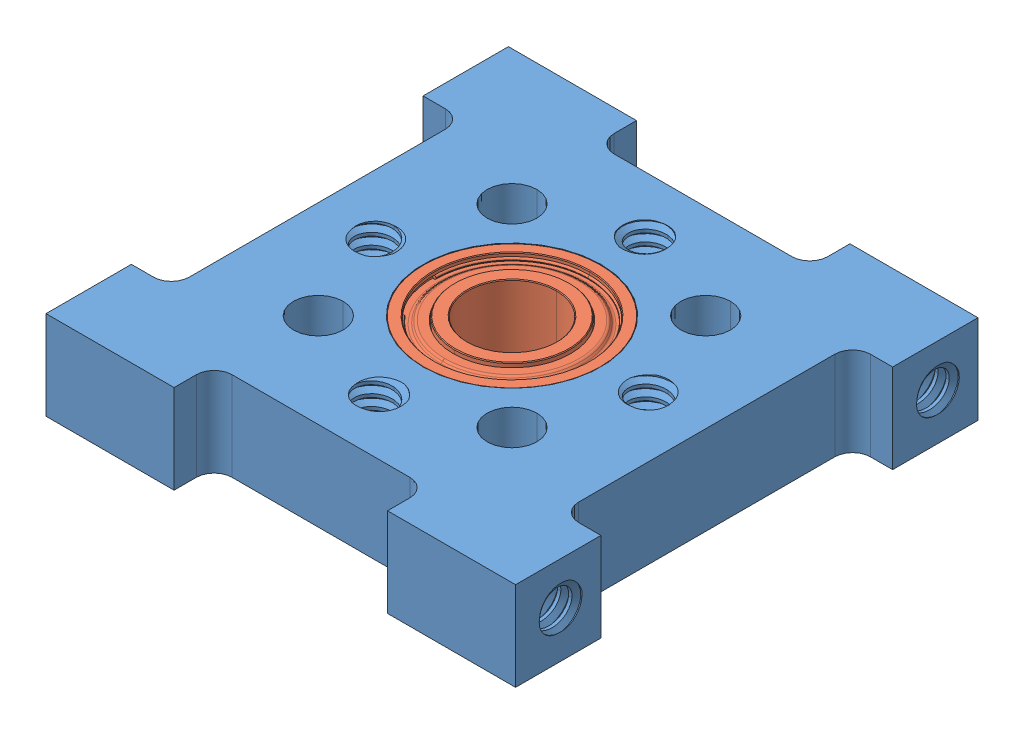
SolidWorks assembly 535130 assembly.STEP, configuration Default. Lengths in mm.
Overall size (33.54 6.36 33.02).
2 component instances, 2 part files, 0 mates.
Components (placement in the parent):
- 535130.STEP-1: 535130.STEP [Default] at (7.6184 14.2154 28.3917) size (33.54 6.36 33.02)
- 535020.STEP-1: 535020.STEP [Default] at (7.6184 18.1715 28.3917) size (12.7 4.76 12.7)
